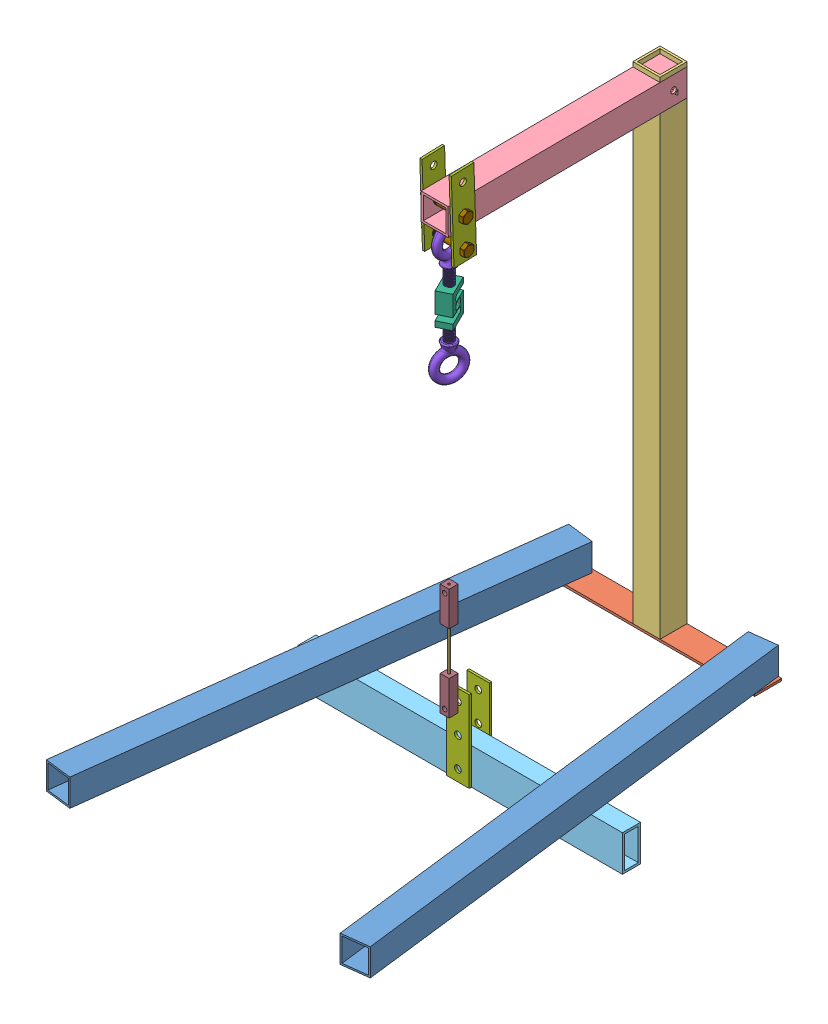
SolidWorks assembly Crane_Asm, configuration Default. Lengths in mm.
Overall size (914.4 1533.68 1320.5).
22 component instances, 13 part files, 46 mates.
Components (placement in the parent):
- Crane_Leg-1: Crane_Leg [Default] at (35.4785 171.5799 115.8909) x (0.992546 0 0.121869) z (-0.121869 0 0.992546) size (76.2 76.2 1320.8)
- Crane_Leg-2: Crane_Leg [Default] at (550.7341 171.5799 115.8909) x (0.992546 0 -0.121869) z (0.121869 0 0.992546) size (76.2 76.2 1320.8)
- Crane_Plate-1: Crane_Plate [Default] at (293.1063 133.4799 149.3477) x (1 0 0) z (0 -1 0) size (609.6 76.2 6.35)
- Crane_Strut-1: Crane_Strut [Default] at (293.1063 1505.0799 149.3477) x (1 0 0) z (0 -1 0) size (76.2 76.2 1371.6)
- Crane_Arm-1: Crane_Arm [Default] at (293.1063 1452.2646 447.7909) x (1 0 0) z (0 -0.006752 0.999977) size (76.2 76.2 673.1)
- Lower_Cross_Bar-1: Lower_Cross_Bar [Default] at (293.1063 82.6799 687.0105) x (0 1 0) z (-1 0 0) size (101.63 50.8 914.4)
- Load_Cell_s-1: Load_Cell_s [Default] at (300.1115 1227.9494 757.7452) x (-0.441269 0 -0.897375) z (0.897375 0 -0.441269) size (63.5 88.9 38.1)
- Hole_Plate-1: Hole_Plate [Default] at (248.6563 1450.2493 746.2341) x (0 0.999451 0.033128) z (1 0 0) size (228.6 63.5 6.35)
- Hole_Plate-2: Hole_Plate [Default] at (337.5563 1450.2493 746.2341) x (0 -0.999451 -0.033128) z (-1 0 0) size (228.6 63.5 6.35)
- Eyebolt-1: Eyebolt [3014T55] at (293.1063 1367.7447 743.4993) x (0 0 1) z (-1 0 0) size (90.49 169.56 39.69)
- Eyebolt-3: Eyebolt [3014T55] at (293.1063 1062.7542 743.4993) x (-0.286373 0 0.958118) z (0.958118 0 0.286373) size (90.49 169.56 39.69)
- 0.75_10_4.5in_Bolt-1: 0.75_10_4.5in_Bolt [91257A852] at (267.7063 1450.2493 746.2341) x (0 0 -1) z (1 0 0) size (28.57 32.74 126.56)
- 0.75_10_4.5in_Bolt-2: 0.75_10_4.5in_Bolt [91257A852] at (267.7063 1367.7447 743.4993) x (0 0 -1) z (1 0 0) size (28.57 32.74 126.56)
- 0.75_hex_nut-1: 0.75_hex_nut [94895A036] at (248.6563 1367.7447 743.4993) x (0 1 0) z (0 0 1) size (28.57 16.27 36.29)
- 0.75_hex_nut-2: 0.75_hex_nut [94895A036] at (248.6563 1450.2493 746.2341) x (0 1 0) z (0 0 1) size (28.57 16.27 36.29)
- 0.75in_washer-1: 0.75in_washer [98038A274] at (328.9203 1367.7447 743.4993) x (0 0.001704 0.999999) z (-1 0 0) size (37.31 37.31 2.29)
- Hole_Plate-5: Hole_Plate [Default] at (293.1063 146.1799 712.4105) x (0 1 0) z (0 0 1) size (228.6 63.5 6.35)
- Hole_Plate-6: Hole_Plate [Default] at (293.1063 146.1799 655.2605) x (0 1 0) z (0 0 1) size (228.6 63.5 6.35)
- PSAS-6DOF-Square_Rod_Test-1: PSAS-6DOF-Square_Rod_Test [Default] at (270.2654 458.0856 795.146) x (-0.906317 0 -0.422598) z (0 -1 0) size (33.75 33.75 314.37)
  - PSAS-6DOF-Fiber_Rod-1: PSAS-6DOF-Fiber_Rod [Default] at (1.1246 56.4608 -38.9521) size (6.1 6.1 254)
  - PSAS-6DOF-Square_Rod_Text_Fixture-1: PSAS-6DOF-Square_Rod_Text_Fixture [Default] at (1.1246 56.4608 245.2308) x (-0.422598 -0.906317 0) z (0 0 -1) size (25.4 25.4 96.52)
  - PSAS-6DOF-Square_Rod_Text_Fixture-2: PSAS-6DOF-Square_Rod_Text_Fixture [Default] at (1.1246 56.4608 -69.1349) x (-0.422598 -0.906317 0) z (0 0 1) size (25.4 25.4 96.52)
Mates (geometry in assembly coordinates):
- Coincident2: coincident anti-aligned: plane of Crane_Leg-1 through (-163.3025 133.4799 1422.2026) normal (0 -1 0); plane of Crane_Plate-1 through (597.9063 133.4799 187.4477) normal (0 1 0)
- Coincident3: coincident anti-aligned: plane of Crane_Leg-2 through (673.8831 133.4799 1431.4891) normal (0 -1 0); plane of Crane_Plate-1 through (597.9063 133.4799 187.4477) normal (0 1 0)
- Angle2: planar angle = 0.122173 rad aligned: plane of Crane_Leg-2 through (749.5151 133.4799 1422.2026) normal (0.992546 0 -0.121869); plane of Crane_Plate-1 through (597.9063 127.1299 111.2477) normal (1 0 0)
- Angle3: planar angle = 0.122173 rad aligned: plane of Crane_Leg-1 through (-163.3025 133.4799 1422.2026) normal (-0.992546 0 -0.121869); plane of Crane_Plate-1 through (-11.6937 127.1299 111.2477) normal (-1 0 0)
- Coincident7: coincident: line of Crane_Leg-1 through (-2.3375 209.6799 111.2477) axis (0 -1 0); plane of Crane_Plate-1 through (-11.6937 127.1299 111.2477) normal (0 0 -1)
- Coincident8: coincident: line of Crane_Leg-2 through (588.5501 133.4799 111.2477) axis (0 1 0); plane of Crane_Plate-1 through (-11.6937 127.1299 111.2477) normal (0 0 -1)
- Coincident9: coincident: plane of Crane_Leg-2 through (749.5151 133.4799 1422.2026) normal (0.992546 0 -0.121869); line of Crane_Plate-1 through (597.9063 127.1299 187.4477) axis (0 1 0)
- Coincident10: coincident: plane of Crane_Leg-1 through (-163.3025 133.4799 1422.2026) normal (-0.992546 0 -0.121869); line of Crane_Plate-1 through (-11.6937 127.1299 187.4477) axis (0 1 0)
- Coincident11: coincident anti-aligned: plane of Crane_Plate-1 through (597.9063 133.4799 187.4477) normal (0 1 0); plane of Crane_Strut-1 through (331.2063 133.4799 187.4477) normal (0 -1 0)
- Coincident12: coincident aligned: plane of Crane_Plate-1 through (-11.6937 127.1299 111.2477) normal (0 0 -1); plane of Crane_Strut-1 through (255.0063 133.4799 111.2477) normal (0 0 -1)
- Coincident13: coincident aligned: plane of Crane_Plate-1; plane of Crane_Strut-1
- Coincident14: coincident aligned: axis of Crane_Strut-1 through (255.0063 1454.2799 149.3477) axis (1 0 0); axis of Crane_Arm-1 through (255.0063 1454.2799 149.3477) axis (1 0 0)
- Coincident15: coincident aligned: plane of Crane_Strut-1; plane of Crane_Arm-1
- Coincident20: coincident anti-aligned: plane of Crane_Arm-1 through (255.0063 1411.8929 784.0759) normal (-1 0 0); plane of Hole_Plate-1 through (255.0063 1563.4348 781.7532) normal (1 0 0)
- Coincident23: coincident anti-aligned: plane of Crane_Arm-1 through (331.2063 1411.8929 784.0759) normal (1 0 0); plane of Hole_Plate-2 through (331.2063 1334.9603 774.1801) normal (-1 0 0)
- Coincident26: coincident aligned: axis of Load_Cell_s-1 through (293.1063 1243.8244 743.4993) axis (0 1 0); axis of Eyebolt-1 through (293.1063 1311.2768 743.4993) axis (0 1 0)
- Coincident27: coincident aligned: plane of Load_Cell_s-1 through (296.191 1243.8244 706.6015) normal (0 -1 0); plane of Eyebolt-1 through (280.4063 1243.8244 743.4993) normal (0 -1 0)
- Coincident29: coincident anti-aligned: plane of Crane_Arm-1; plane of Eyebolt-1 through (293.1063 1367.7447 743.4993) normal (-1 0 0)
- Coincident32: coincident aligned: axis of Load_Cell_s-1 through (293.1063 1186.6744 743.4993) axis (0 -1 0); axis of Eyebolt-3 through (293.1063 1126.2888 743.4993) axis (0 -1 0)
- Coincident33: coincident aligned: plane of Load_Cell_s-1 through (324.2116 1186.6744 763.5848) normal (0 1 0); plane of Eyebolt-3 through (305.2744 1186.6744 747.1363) normal (0 1 0)
- Coincident59: coincident anti-aligned: axis of Hole_Plate-2 through (337.5563 1367.7447 743.4993) axis (-1 0 0); axis of Eyebolt-1 through (267.7741 1367.7447 743.4993) axis (1 0 0)
- Coincident61: coincident anti-aligned: axis of Hole_Plate-1 through (248.6563 1367.7447 743.4993) axis (1 0 0); axis of Hole_Plate-2 through (337.5563 1367.7447 743.4993) axis (-1 0 0)
- Coincident62: coincident aligned: axis of Crane_Arm-1 through (324.8563 1450.2493 746.2341) axis (1 0 0); axis of Hole_Plate-1 through (248.6563 1450.2493 746.2341) axis (1 0 0)
- Coincident64: coincident anti-aligned: axis of Crane_Arm-1 through (324.8563 1450.2493 746.2341) axis (1 0 0); axis of Hole_Plate-2 through (337.5563 1450.2493 746.2341) axis (-1 0 0)
- Coincident65: coincident anti-aligned: plane of Hole_Plate-2 through (337.5563 1334.9603 774.1801) normal (1 0 0); plane of 0.75_10_4.5in_Bolt-1 through (337.5563 1466.7471 746.2341) normal (-1 0 0)
- Coincident66: coincident anti-aligned: axis of Crane_Arm-1 through (324.8563 1450.2493 746.2341) axis (1 0 0); axis of 0.75_10_4.5in_Bolt-1 through (335.6513 1450.2493 746.2341) axis (-1 0 0)
- Coincident67: coincident anti-aligned: axis of Eyebolt-1 through (267.7741 1367.7447 743.4993) axis (1 0 0); axis of 0.75_10_4.5in_Bolt-2 through (335.6513 1367.7447 743.4993) axis (-1 0 0)
- Coincident68: coincident anti-aligned: plane of Hole_Plate-2 through (337.5563 1334.9603 774.1801) normal (1 0 0); plane of 0.75_10_4.5in_Bolt-2 through (337.5563 1384.2424 743.4993) normal (-1 0 0)
- Coincident69: coincident anti-aligned: plane of Hole_Plate-1 through (248.6563 1563.4348 781.7532) normal (-1 0 0); plane of 0.75_hex_nut-2 through (248.6563 1450.2493 729.7363) normal (1 0 0)
- Coincident70: coincident anti-aligned: axis of 0.75_10_4.5in_Bolt-1 through (230.8046 1450.2493 746.2341) axis (-1 0 0); axis of 0.75_hex_nut-2 through (238.5757 1450.2493 746.2341) axis (1 0 0)
- Coincident71: coincident anti-aligned: plane of Hole_Plate-1 through (248.6563 1563.4348 781.7532) normal (-1 0 0); plane of 0.75_hex_nut-1 through (248.6563 1367.7447 727.0016) normal (1 0 0)
- Coincident72: coincident aligned: axis of 0.75_10_4.5in_Bolt-2 through (230.8046 1367.7447 743.4993) axis (-1 0 0); axis of 0.75_hex_nut-1 through (235.6953 1367.7447 743.4993) axis (-1 0 0)
- Coincident73: coincident anti-aligned: axis of Eyebolt-1 through (267.7741 1367.7447 743.4993) axis (1 0 0); axis of 0.75in_washer-1 through (331.2063 1367.7447 743.4993) axis (-1 0 0)
- Coincident74: coincident anti-aligned: plane of Hole_Plate-2 through (331.2063 1334.9603 774.1801) normal (-1 0 0); plane of 0.75in_washer-1 through (331.2063 1367.7447 743.4993) normal (1 0 0)
- Coincident75: coincident aligned: plane of Hole_Plate-5 through (324.8563 31.8799 718.7605) normal (0 -1 0); plane of Hole_Plate-6 through (324.8563 31.8799 661.6105) normal (0 -1 0)
- Coincident81: coincident aligned: plane of Crane_Plate-1 through (597.9063 133.4799 187.4477) normal (0 1 0); plane of Lower_Cross_Bar-1 through (-164.0937 133.4799 712.4105) normal (0 1 0)
- Parallel5: parallel anti-aligned: plane of Crane_Plate-1 through (-11.6937 127.1299 187.4477) normal (0 0 1); plane of Lower_Cross_Bar-1 through (-164.0937 31.8799 661.6105) normal (0 0 -1)
- Coincident83: coincident anti-aligned: plane of Lower_Cross_Bar-1 through (-164.0937 31.8799 712.4105) normal (0 0 1); plane of Hole_Plate-5 through (261.3563 260.4799 712.4105) normal (0 0 -1)
- Coincident84: coincident aligned: plane of Lower_Cross_Bar-1 through (-164.0937 31.8799 712.4105) normal (0 -1 0); plane of Hole_Plate-5 through (324.8563 31.8799 718.7605) normal (0 -1 0)
- Coincident86: coincident anti-aligned: plane of Lower_Cross_Bar-1 through (-164.0937 31.8799 661.6105) normal (0 0 -1); plane of Hole_Plate-6 through (261.3563 260.4799 661.6105) normal (0 0 1)
- Coincident87: coincident aligned: plane of Hole_Plate-5; plane of Hole_Plate-6
- Coincident88: coincident aligned: plane of Lower_Cross_Bar-1 through (293.1063 82.6799 687.0105) normal (-1 0 0); plane of Hole_Plate-5
- Coincident89: coincident anti-aligned: plane of Crane_Plate-1; plane of Lower_Cross_Bar-1 through (293.1063 82.6799 687.0105) normal (-1 0 0)
- Coincident90: coincident anti-aligned: axis of Hole_Plate-5 through (293.1063 228.7299 712.4105) axis (0 0 1); axis of PSAS-6DOF-Square_Rod_Test-1/PSAS-6DOF-Square_Rod_Text_Fixture-1 through (293.1063 228.7299 756.1993) axis (0 0 -1)
- Coincident91: coincident anti-aligned: axis of Load_Cell_s-1 through (293.1063 1186.6744 743.4993) axis (0 -1 0); axis of PSAS-6DOF-Square_Rod_Test-1/PSAS-6DOF-Fiber_Rod-1 through (293.1063 243.0377 743.4993) axis (0 1 0)
- Coincident92: coincident anti-aligned: axis of Crane_Arm-1 through (324.8563 1450.2493 746.2341) axis (1 0 0); axis of Hole_Plate-2 through (337.5563 1450.2493 746.2341) axis (-1 0 0)
